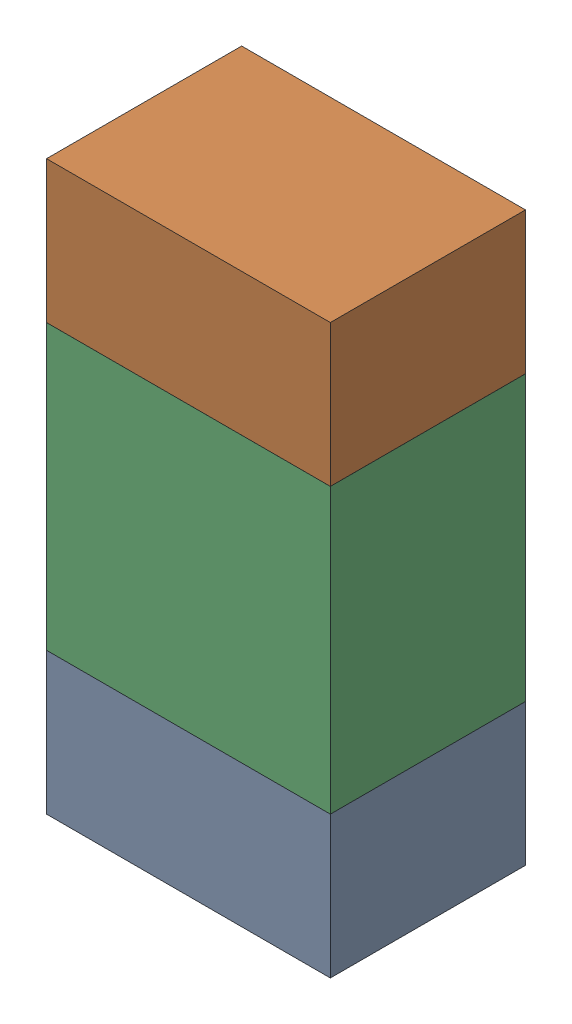
SolidWorks assembly R8, configuration ﾃﾞﾌｫﾙﾄ. Lengths in mm.
Overall size (0.8 1.6 0.55).
6 component instances, 2 part files, 0 mates.
Components (placement in the parent):
- 689261784-1: 689261784 [ﾃﾞﾌｫﾙﾄ] at (9.9999 24.1501 0) size (0.8 0.4 0.55)
  - Extruded_34-1: Extruded_34 [ﾃﾞﾌｫﾙﾄ] at origin size (0.8 0.4 0.55)
- 689261784-2: 689261784 [ﾃﾞﾌｫﾙﾄ] at (9.9999 25.3501 0) size (0.8 0.4 0.55)
  - Extruded_34-1: Extruded_34 [ﾃﾞﾌｫﾙﾄ] at origin size (0.8 0.4 0.55)
- 689261648-1: 689261648 [ﾃﾞﾌｫﾙﾄ] at (9.9999 24.75 0) size (0.8 0.8 0.55)
  - Extruded_33-1: Extruded_33 [ﾃﾞﾌｫﾙﾄ] at origin size (0.8 0.8 0.55)
